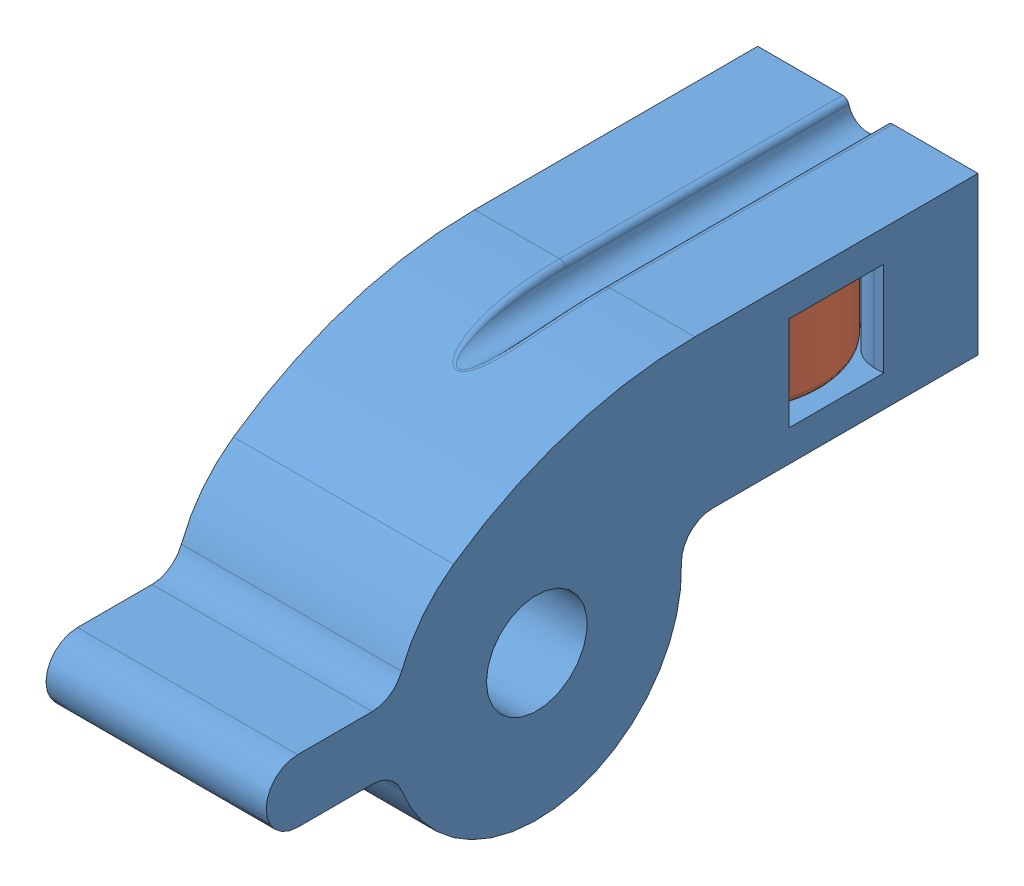
SolidWorks assembly Finger With Magnet, configuration Default. Lengths in mm.
Overall size (7.5 10.88 22.62).
2 component instances, 2 part files, 6 mates.
Components (placement in the parent):
- finger-1: finger [Default] x (0 0 -1) z (-1 0 0) size (22.62 10.88 7.5)
- magnet-1: magnet [Default] at (0 3.6875 -9.525) x (0 0 1) z (-1 0 0) size (6 3 6)
Mates (geometry in assembly coordinates):
- Concentric1: concentric anti-aligned: cylinder of finger-1 through (-3.5 0 0) axis (1 0 0) radius 1.6
- Coincident1: coincident anti-aligned: plane of finger-1 through (0 0 0) normal (-1 0 0)
- Coincident2: coincident anti-aligned: plane of finger-1 through (0 0 0) normal (0 -1 0)
- Concentric2: concentric anti-aligned: cylinder of finger-1 through (0 -4.602 -9.525) axis (0 1 0) radius 3.05; cylinder of magnet-1 through (0 5.1875 -9.525) axis (0 -1 0) radius 3
- Coincident3: coincident anti-aligned: plane of finger-1 through (-3.5 2.1875 -6.025) normal (0 1 0); plane of magnet-1 through (0 2.1875 -9.525) normal (0 -1 0)
- Coincident4: coincident anti-aligned: plane of magnet-1 through (0 3.6875 -9.525) normal (-1 0 0)
